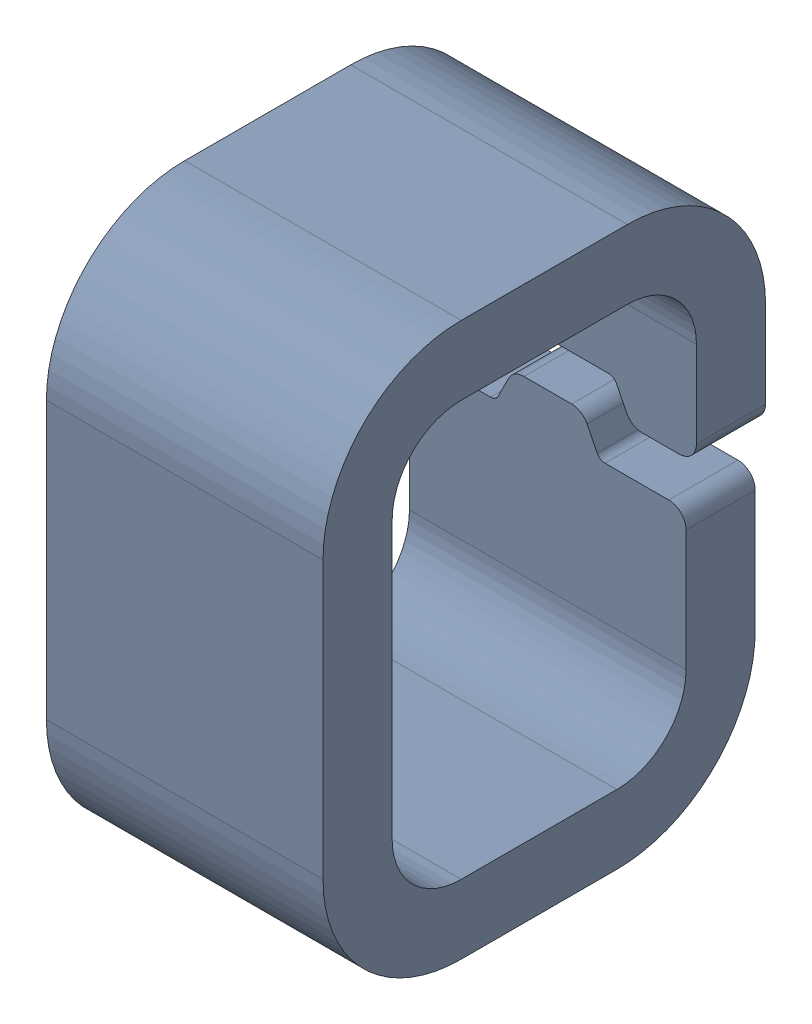
SolidWorks assembly TP5, configuration Default. Lengths in mm.
Overall size (0.8 1.6 1.28).
2 component instances, 1 part files, 0 mates.
Components (placement in the parent):
- Conn_Harwin_S2761-46R_eec-1: Conn_Harwin_S2761-46R_eec [Default] at (24.003 -4.953 0) x (0 1 0) z (0 0 1) size (1.6 0.8 1.28)
  - TP-1: TP [Default] at origin size (1.6 0.8 1.28)
